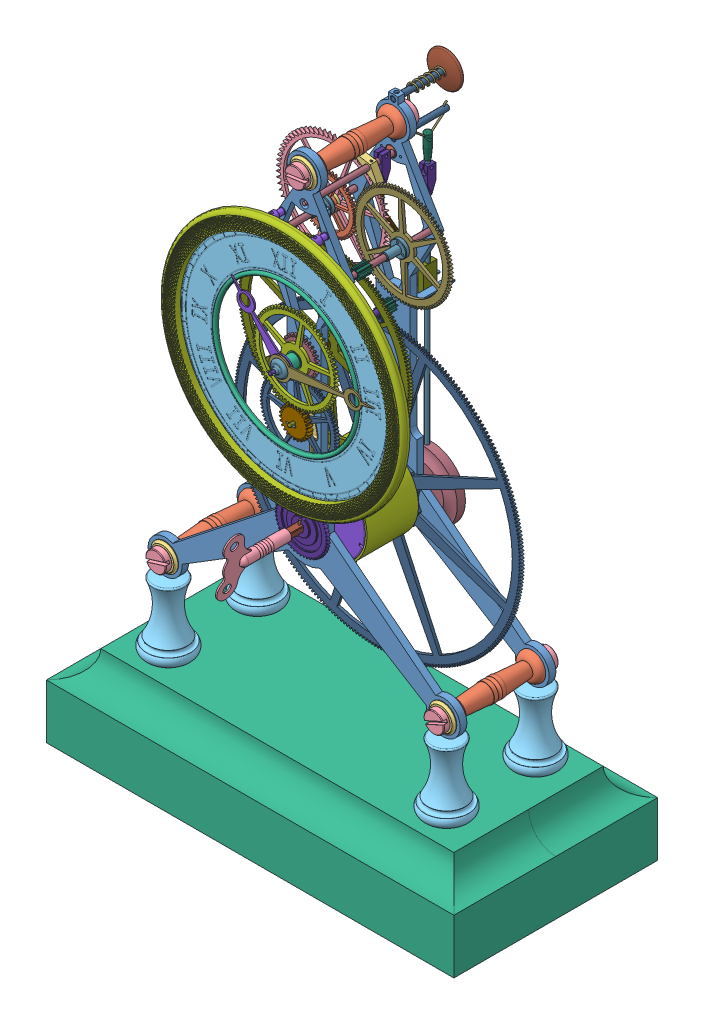
SolidWorks assembly clock, configuration Default. Lengths in mm.
Overall size (300 450.9 172.25).
96 component instances, 58 part files, 79 mates.
Components (placement in the parent):
- frame assy-1: frame assy [Default] at origin size (300 436.05 150)
  - Frame-1: Frame [Front] at origin size (229.79 321.19 5)
  - pillar-1: pillar [Default] at (0 115.9979 0) size (20 20 70.93)
  - pillar-2: pillar [Default] at (102.394 -180.1971 0) x (0.987351 0.158553 0) z (0 0 1) size (20 20 70.93)
  - pillar-3: pillar [Default] at (-102.394 -180.1971 0) x (0.959125 0.282984 0) z (0 0 1) size (20 20 70.93)
  - Frame-2: Frame [Back] at (0 0 -60.5) x (-1 0 0) z (0 0 -1) size (229.79 326.05 5)
  - washer-1: washer [Default] at (0 115.9979 7) x (0.258664 -0.965967 0) z (0 0 -1) size (20 20 2)
  - frame screw-1: frame screw [Default] at (0 115.9979 7) x (-0.137342 0.990524 0) z (0.990524 0.137342 0) size (15 20 15)
  - frame screw-2: frame screw [Default] at (-102.394 -180.1971 7) x (-0.292655 0.956218 0) z (0.956218 0.292655 0) size (15 20 15)
  - washer-2: washer [Default] at (-102.394 -180.1971 7) x (0.408549 -0.912737 0) z (0 0 -1) size (20 20 2)
  - frame screw-4: frame screw [Default] at (102.394 -180.1971 7) x (0.41203 -0.91117 0) z (-0.91117 -0.41203 0) size (15 20 15)
  - washer-4: washer [Default] at (102.394 -180.1971 7) x (-0.521444 0.853286 0) z (0 0 -1) size (20 20 2)
  - frame screw-6: frame screw [Default] at (102.394 -180.1971 -67.5) x (0.92649 0.37632 0) z (-0.37632 0.92649 0) size (15 20 15)
  - washer-6: washer [Default] at (102.394 -180.1971 -67.5) x (-0.965884 -0.258974 0) z (0 0 1) size (20 20 2)
  - frame screw-8: frame screw [Default] at (-102.394 -180.1971 -67.5) x (-0.887501 -0.460806 0) z (0.460806 -0.887501 0) size (15 20 15)
  - washer-8: washer [Default] at (-102.394 -180.1971 -67.5) x (-0.90624 -0.422764 0) z (0 0 1) size (20 20 2)
  - frame screw-10: frame screw [Default] at (0 115.9979 -67.5) x (0.741906 0.670504 0) z (-0.670504 0.741906 0) size (15 20 15)
  - washer-10: washer [Default] at (0 115.9979 -67.5) x (-0.81906 -0.573708 0) z (0 0 1) size (20 20 2)
  - foot-1: foot [Default] at (-102.394 -242.6971 2.5) x (0.145571 0 -0.989348) z (0.989348 0 0.145571) size (34 49.97 34)
  - foot-2: foot [Default] at (102.394 -242.6971 2.5) x (-0.043484 0 -0.999054) z (0.999054 0 -0.043484) size (34 49.97 34)
  - foot-3: foot [Default] at (102.394 -242.6971 -63) x (-0.257831 0 -0.96619) z (0.96619 0 -0.257831) size (34 49.97 34)
  - foot-4: foot [Default] at (-102.394 -242.6971 -63) x (-0.477152 0 -0.878821) z (0.878821 0 -0.477152) size (34 49.97 34)
  - base-1: base [Default] at (0 -302.6971 -30.25) size (300 60 150)
- barrel assy-1: barrel assy [Default] at (-35.1643 -5.8563 0) x (0.946025 0.324095 0) z (0 0 1) size (297.48 297.48 41.9)
  - barrel-1: barrel [Default] at (-66.9035 -193.9176 -9.3) x (-0.787259 0.616622 0) z (0 0 1) size (60 60 37.9)
  - barrel front cap-1: barrel front cap [Default] at (-66.9035 -193.9176 -9.3) x (-0.787259 0.616622 0) z (0 0 1) size (57.64 57.6 4.06)
  - barrel rear cap-1: barrel rear cap [Default] at (-66.9035 -193.9176 -51.2) x (0.787259 -0.616622 0) z (0 0 -1) size (57.6 57.6 4)
  - great wheel-1: great wheel [Default] at (85.4176 -175.4035 -49.2) x (-0.616622 -0.787259 0) z (0 0 1) size (211.89 211.9 2)
- barrel arbor-1: barrel arbor [Default] at (-106.8134 -89.4436 0) x (0.175635 0.984455 0) z (0 0 1) size (12 13 98.5)
- third wheel assy-1: third wheel assy [Default] at (-56.1519 28.3418 33.0931) x (0.998621 0.052495 0) z (0 0 1) size (71.86 71.91 71.9)
  - third wheel-1: third wheel [Default] at (57.6984 -32.7767 -72.5931) size (71.86 71.91 2)
  - top arbor-1: top arbor [Default] at (85.1984 27.2212 -93.5931) x (-0.979838 0.199793 0) z (0 0 -1) size (4 4 71.9)
  - escape collet-1: escape collet [Default] at (46.9887 81.0358 -78.5931) x (0.5 0.866025 0) z (0 0 -1) size (12 12 19)
  - great pinion-1: great pinion [Default] at (85.1984 27.2212 -37.9189) x (0.985823 -0.167791 0) z (0 0 1) size (8.11 8.11 10)
- center wheel assy-1: center wheel assy [Default] x (-0.992046 -0.125879 0) z (0 0 1) size (127.02 127.02 96.9)
  - great pinion-1: great pinion [Default] at (0 0 -50.2) size (8.11 8.11 10)
  - center wheel-1: center wheel [Default] at (0 0 -10) x (1 -0.000968 0) z (0 0 1) size (126.9 126.9 2)
  - center arbor-1: center arbor [Default] at origin size (4 4 96.9)
  - center collet-1: center collet [Default] at (0 0 -10) size (18 18 16)
  - motionwork taper pin-1: motionwork taper pin [Default] at (0 0 29.2) size (7 0.99 0.99)
- escape wheel assy-1: escape wheel assy [Default] at (-72.062 104.0263 94.3243) x (-0.943189 -0.03152 0.330758) z (0.331853 -0.138437 0.933118) size (103.61 105.97 68.71)
  - escape collet-1: escape collet [Default] at (-100.675 125.491 -95.1936) x (0.749598 0.639959 -0.168982) z (-0.330758 0.141033 -0.933118) size (12 12 19)
  - escape drive wheel-1: escape drive wheel [Default] at (-82.6947 -3.3757 -114.6141) x (0.871313 -0.334178 -0.359359) z (0.330758 -0.141033 0.933118) size (41.81 41.89 2)
  - escape spacer-1: escape spacer [Default] at (-83.3563 -3.0937 -116.4803) x (0.871313 -0.334178 -0.359359) z (0.330758 -0.141033 0.933118) size (12 12 2)
  - top arbor-1: top arbor [Default] at (-91.852 64.6878 -123.5861) x (-0.902259 0.242585 0.356484) z (-0.330758 0.141033 -0.933118) size (4 4 71.9)
  - escape wheel-1: escape wheel [Default] at (-84.0178 -2.8116 -118.3465) x (0.871313 -0.334178 -0.359359) z (0.330758 -0.141033 0.933118) size (83.42 83.5 2)
  - escape screw-1: escape screw [Default] at (-90.634 61.8662 -108.3692) x (0.929342 0.220591 -0.296079) z (-0.164081 0.965116 0.20403) size (4 12 4)
  - escape screw-2: escape screw [Default] at (-85.4406 66.2999 -109.5399) x (0.886772 0.384713 -0.256184) z (-0.322853 0.912198 0.252311) size (4 12 4)
  - escape screw-4: escape screw [Default] at (-84.5973 59.5509 -110.8589) x (0.837371 0.499848 -0.221271) z (-0.435211 0.854553 0.283426) size (4 12 4)
- motionwork hour assy-1: motionwork hour assy [Default] at (0 0 1.5) x (-0.682615 0.730778 0) z (0 0 1) size (85.92 61.91 12)
  - motionwork hour pipe-1: motionwork hour pipe [Default] at origin size (10.5 10.5 12)
  - hour wheel-1: hour wheel [Default] at (0 0 10.5) size (61.84 61.91 2)
  - motionwork hour hand-1: motionwork hour hand [Default] at origin size (63 16 1)
- motionwork reduction assy-1: motionwork reduction assy [Default] at (-19.1342 -75.1267 9) x (-0.878167 0.478354 0) z (0 0 1) size (56.89 56.89 5.5)
  - motionwork reduction pinion-1: motionwork reduction pinion [Default] at origin size (21.83 21.79 5.5)
  - motionwork reduction wheel-1: motionwork reduction wheel [Default] at origin size (56.89 56.89 2)
- motionwork minute assy-1: motionwork minute assy [Default] x (0.992046 0.125879 0) z (0 0 1) size (83.37 26.88 22)
  - motionwork minute pipe-1: motionwork minute pipe [Default] at origin size (7 7 18)
  - motionwork minute hand-1: motionwork minute hand [Default] at (0 0 3) size (78 16 1)
  - motionwork minute pinion-1: motionwork minute pinion [Default] at (0 0 8.5) size (26.73 26.88 2)
  - motionwork endcap-1: motionwork endcap [Default] at (0 0 23) size (12 12 4)
  - motionwork minute hand support-1: motionwork minute hand support [Default] at (0 0 22) size (12 12 3)
- motionwork reduction pivot-1: motionwork reduction pivot [Default] at (0 0 5) size (3 3 16.7)
- motionwork taper pin-1: motionwork taper pin [Default] at (0 -40 14.75) x (-1 0 0) z (0 0 1) size (7 0.99 0.99)
- barrel rachet wheel-1: barrel rachet wheel [Default] at (19.0564 -1.6866 7) x (0.984455 -0.175635 0) z (0 0 1) size (38.92 39 3)
- barrel click-1: barrel click [Default] at (0 0 7) size (17.17 29.82 2)
- barrel assy shoulder bolt-1: barrel assy shoulder bolt [Default] at (0 0 7) size (8.5 8.5 10.5)
- barrel click taper pin-1: barrel click taper pin [Default] at (0 -108.5 9) x (0.175635 0.984455 0) z (-0.867067 0.154692 0.473566) size (12 1.36 1.36)
- barrel click spring-1: barrel click spring [Default] at (0 0 5) size (8.83 43.99 1.56)
- winding key-1: winding key [Default] at (19.0564 -1.6866 18) x (0.984455 -0.175635 0) z (0 0 1) size (8 45 49)
- chapter ring assy-1: chapter ring assy [Default] at (0 0 17) size (180 180 23.64)
  - chapter ring-1: chapter ring [Default] at origin size (160 160 1)
  - chapter ring inner bezel-1: chapter ring inner bezel [Default] at (0 0 1) x (0.995864 0.090862 0) z (0 0 1) size (108 108 2.5)
  - chapter ring outer bezel-1: chapter ring outer bezel [Default] at origin size (180 180 5.64)
  - chapter ring post-1: chapter ring post [Default] at (15.9651 83.4872 -12) x (0 -1 0) z (0 0 1) size (6 6 17)
  - chapter ring post screw-1: chapter ring post screw [Default] at (-15.9651 83.4872 -5) size (6 6 7.04)
  - chapter ring post screw-2: chapter ring post screw [Default] at (15.9651 83.4872 -5) x (0.987351 0.158553 0) z (0 0 1) size (6 6 7.04)
  - chapter ring post-2: chapter ring post [Default] at (-15.9651 83.4872 -12) x (0 -1 0) z (0 0 1) size (6 6 17)
- suspension post-1: suspension post [Default] at (100.8262 102.1394 -65.5) x (0 1 0) z (0 0 1) size (4 4 40)
- suspension post-2: suspension post [Default] at (100.8262 77.1394 -65.5) x (0 1 0) z (0 0 1) size (4 4 40)
- suspension knob-1: suspension knob [Default] at (0 129.9979 -100) x (0.799165 0.601111 0) z (-0.601111 0.799165 0) size (26 3.95 26)
- suspension rope-1: suspension rope [Default] at (0 0 -74) size (8.06 39.53 26.52)
- pendulum assy-1: pendulum assy [Default] at (-0.6668 -128.0011 -86) x (-0.999996 0.00299 0) z (0 0 -1) size (50.8 250.4 12)
  - pendulum bob-1: pendulum bob [Default] at origin size (50.8 50.8 12)
  - pendulum rod-1: pendulum rod [Default] at (0 15 0) size (3 200 3)
  - pendulum hook-1: pendulum hook [Default] at (0 215 0) x (0 0 1) z (-1 0 0) size (5 18 5)
  - pendulum block-1: pendulum block [Default] at (0 116.5269 0) x (0 0 1) z (-1 0 0) size (10 25 4)
  - pendulum layout-1: pendulum layout [Default] at origin
  - crutch top-1: crutch top [Default] at origin size (7.17 20 7.17)
  - crutch rod-1: crutch rod [Default] at origin size (2 91.36 22) (hidden)
- top arbor-1: top arbor [Default] at (0 95.9979 -60.5) x (0.8635 0.504349 0) z (0 0 -1) size (4 4 71.9)
- crutch top-1: crutch top [Default] at (-0.598 -104.0012 -52.5) x (0.999996 -0.00299 0) z (0 0 1) size (7.17 20 7.17)
- crutch rod-1: crutch rod [Default] at (-0.2881 -0.3606 -72.5) x (0.999996 -0.00299 0) z (0 0 1) size (2 91.36 22)
- crutch pallet-1: crutch pallet [Default] at (-0.2911 -1.3606 -72.5) x (0 0 -1) z (0.999996 -0.00299 0) size (30 10 16)
- eccentric bushing-1: eccentric bushing [Default] at (0 191.9958 -65.5) x (-1 0 0) z (0 0 1) size (10.4 10.4 7)
- escape pallets-1: escape pallets [Default] at (0 0 -46.5) size (18.3 15.59 5)
Mates (geometry in assembly coordinates):
- GearMate2: gear = 8 : 180 mm: cylinder of center wheel assy-1/center wheel-1 through (0 0 -12) axis (0 0 1) radius 56.5496; cylinder of third wheel assy-1/top arbor-1 through (27.5 59.9979 5) axis (0 0 1) radius 2
- GearMate3: gear = 50 : 90 mm: cylinder of third wheel assy-1/third wheel-1 through (27.5 59.9979 -41.5) axis (0 0 1) radius 30.0469; cylinder of escape wheel assy-1/escape drive wheel-1 through (-27.5 59.9979 -41.5) axis (0 0 1) radius 16.0474
- Concentric32: concentric: cylinder of center wheel assy-1/center arbor-1 through (0 0 29.2339) axis (0 0 1) radius 1.25; cylinder of motionwork minute assy-1/motionwork minute pipe-1 through (0 0 23) axis (0 0 -1) radius 3.5
- Concentric33: concentric: cylinder of motionwork hour assy-1/motionwork hour pipe-1 through (0 0 21.5) axis (0 0 -1) radius 3.5; cylinder of motionwork minute assy-1/motionwork minute pipe-1 through (0 0 23) axis (0 0 -1) radius 3.5
- Distance2: distance = 0.5 mm: plane of motionwork hour assy-1/hour wheel-1 through (0 0 12) normal (0 0 1); plane of motionwork reduction assy-1/motionwork reduction pinion-1 through (-19.1342 -75.1267 12.5) normal (0 0 1)
- Coincident24: coincident: plane of center wheel assy-1/center arbor-1 through (0 0 0) normal (0.125879 -0.992046 0); plane of motionwork minute assy-1/motionwork minute pipe-1 through (0 0 0) normal (-0.125879 0.992046 0)
- GearMate4: gear = 30 : 80 mm: circle of motionwork reduction assy-1/motionwork reduction wheel-1; circle of motionwork minute assy-1/motionwork minute pinion-1
- GearMate5: gear = 70 : 25 mm: circle of motionwork reduction assy-1/motionwork reduction pinion-1; circle of motionwork hour assy-1/hour wheel-1
- Coincident26: coincident: plane of motionwork reduction pivot-1 through (0 0 5) normal (1 0 0); plane of motionwork taper pin-1 through (0 -40 14.75) normal (-1 0 0)
- Concentric35: concentric: cylinder of motionwork reduction pivot-1 through (-1.5 -40 14.75) axis (1 0 0) radius 0.4; circle of motionwork taper pin-1
- Concentric36: concentric: cylinder of barrel assy-1/barrel-1 through (0 -108.5 -49.2) axis (0 0 1) radius 30; cylinder of barrel arbor-1 through (0 -108.5 -65.5) axis (0 0 -1) radius 6
- Coincident27: coincident: plane of barrel assy-1/barrel rear cap-1 through (0 -108.5 -47.2) normal (0 0 1); plane of barrel arbor-1 through (5.9067 -109.5538 -47.2) normal (0 0 -1)
- GearMate6: gear = 8 : 290 mm: cylinder of barrel assy-1/great wheel-1 through (0 -108.5 -51.2) axis (0 0 1) radius 99.0488; cylinder of center wheel assy-1/center arbor-1 through (0 0 29.2339) axis (0 0 1) radius 2
- Concentric37: concentric: cylinder of frame assy-1/Frame-1 through (0 -108.5 0) axis (0 0 1) radius 3; cylinder of barrel arbor-1 through (0 -108.5 -65.5) axis (0 0 -1) radius 3
- Coincident28: coincident: plane of frame assy-1/Frame-1 through (0 0 0) normal (0 0 -1); plane of barrel arbor-1 through (2.9534 -109.0269 0) normal (0 0 1)
- Concentric38: concentric: cylinder of frame assy-1/Frame-1 through (-27.5 59.9979 5) axis (0 0 -1) radius 1.25; cylinder of escape wheel assy-1/top arbor-1 through (-27.5 59.9979 5) axis (0 0 1) radius 1.25
- Coincident29: coincident: plane of frame assy-1/Frame-1 through (0 0 0) normal (0 0 -1); plane of escape wheel assy-1/top arbor-1 through (-27.1737 61.2046 0) normal (0 0 1)
- Concentric39: concentric: cylinder of frame assy-1/Frame-1 through (0 0 0) axis (0 0 1) radius 1.25; cylinder of center wheel assy-1/center arbor-1 through (0 0 29.2339) axis (0 0 1) radius 1.25
- Coincident30: coincident: plane of frame assy-1/Frame-1 through (0 0 0) normal (0 0 -1); plane of center wheel assy-1/center arbor-1 through (-0.2518 1.9841 0) normal (0 0 1)
- Concentric40: concentric: cylinder of frame assy-1/Frame-1 through (27.5 59.9979 5) axis (0 0 -1) radius 1.25; cylinder of third wheel assy-1/top arbor-1 through (27.5 59.9979 5) axis (0 0 1) radius 1.25
- Coincident31: coincident: plane of frame assy-1/Frame-1 through (0 0 0) normal (0 0 -1); plane of third wheel assy-1/top arbor-1 through (27.3149 58.7617 0) normal (0 0 1)
- Concentric41: concentric: circle of frame assy-1/Frame-1; circle of motionwork reduction assy-1/motionwork reduction pinion-1
- Distance3: distance = 2 mm: plane of motionwork reduction assy-1/motionwork reduction wheel-1 through (-13.6351 -63.8817 7) normal (0 0 -1); plane of frame assy-1/Frame-1 through (0 0 5) normal (0 0 1)
- Coincident32: coincident: plane of frame assy-1/Frame-1 through (0 0 5) normal (0 0 1); plane of motionwork minute assy-1/motionwork minute pipe-1 through (0 0 5) normal (0 0 -1)
- Coincident33: coincident: plane of frame assy-1/Frame-1 through (0 0 5) normal (0 0 1); plane of motionwork reduction pivot-1 through (0 -40 5) normal (0 0 -1)
- Concentric42: concentric: cylinder of frame assy-1/Frame-1 through (0 -40 0) axis (0 0 1) radius 1.25; cylinder of motionwork reduction pivot-1 through (0 -40 0) axis (0 0 -1) radius 1.25
- Parallel4: parallel: plane of frame assy-1/Frame-1 through (-12.5 0 5) normal (-1 0 0); plane of motionwork reduction pivot-1 through (-1.5 -38.5 7) normal (-1 0 0)
- Coincident34: coincident: plane of frame assy-1/Frame-1 through (0 0 5) normal (0 0 1); plane of barrel rachet wheel-1 through (0 -108.5 5) normal (0 0 -1)
- Parallel5: parallel: plane of barrel arbor-1 through (-2.6929 -110.3775 5) normal (-0.984455 0.175635 0); plane of barrel rachet wheel-1 through (2.8089 -106.5416 5) normal (-0.984455 0.175635 0)
- Concentric43: concentric: circle of barrel arbor-1; circle of barrel rachet wheel-1
- Coincident35: coincident: plane of frame assy-1/Frame-1 through (0 0 5) normal (0 0 1); plane of barrel assy shoulder bolt-1 through (0 -80.5 5) normal (0 0 -1)
- Concentric44: concentric: cylinder of frame assy-1/Frame-1 through (0 -80.5 0) axis (0 0 1) radius 1; cylinder of barrel assy shoulder bolt-1 through (0 -80.5 5) axis (0 0 1) radius 2
- Concentric45: concentric: cylinder of barrel click-1 through (0 -80.5 5) axis (0 0 1) radius 2; cylinder of barrel assy shoulder bolt-1 through (0 -80.5 5) axis (0 0 1) radius 2
- Coincident36: coincident: plane of frame assy-1/Frame-1 through (0 0 5) normal (0 0 1); plane of barrel click-1 through (0 -80.5 5) normal (0 0 -1)
- Coincident37: coincident: plane of frame assy-1/Frame-1 through (0 0 0) normal (0 0 1); plane of assembly through (0 0 0) normal (0 0 1)
- Coincident38: coincident: plane of frame assy-1/Frame-1 through (0 0 0) normal (0 1 0); plane of assembly through (0 0 0) normal (0 1 0)
- Coincident39: coincident: plane of frame assy-1/Frame-1 through (0 0 0) normal (1 0 0); plane of assembly through (0 0 0) normal (1 0 0)
- Parallel6: parallel: plane of frame assy-1/Frame-1 through (17.5 -78.5 5) normal (1 0 0); plane of barrel click-1 through (5 -66.5 5) normal (1 0 0)
- Concentric46: concentric: circle of barrel arbor-1; circle of barrel click taper pin-1
- Coincident40: coincident: plane of barrel arbor-1 through (-106.8134 -89.4436 0) normal (0.175635 0.984455 0); plane of barrel click taper pin-1 through (0 -108.5 9) normal (0.175635 0.984455 0)
- Coincident41: coincident: plane of frame assy-1/Frame-1 through (0 0 5) normal (0 0 1); plane of barrel click spring-1 through (6 -47.5 5) normal (0 0 -1)
- Concentric47: concentric: cylinder of frame assy-1/Frame-1 through (6 -45 0) axis (0 0 1) radius 1; circle of barrel click spring-1
- Concentric48: concentric: cylinder of frame assy-1/Frame-1 through (6 -33 0) axis (0 0 1) radius 0.5; circle of barrel click spring-1
- Coincident42: coincident: plane of barrel arbor-1 through (0 -108.5 30) normal (0 0 1); plane of winding key-1 through (19.0564 -1.6866 30) normal (0 0 -1)
- Concentric49: concentric: cylinder of barrel arbor-1 through (0 -108.5 -65.5) axis (0 0 -1) radius 4; cylinder of winding key-1 through (0 -108.5 53) axis (0 0 -1) radius 4
- Parallel8: parallel: plane of barrel arbor-1 through (-2.6929 -110.3775 5) normal (-0.984455 0.175635 0); line of winding key-1 through (-2.1029 -105.4838 18) axis (-0.175635 -0.984455 0)
- Concentric53: concentric: circle of center wheel assy-1/center arbor-1; circle of chapter ring assy-1/chapter ring-1
- Coincident45: coincident: plane of frame assy-1/Frame-1 through (0 0 5) normal (0 0 1); plane of chapter ring assy-1/chapter ring post-1 through (18.2651 83.4872 5) normal (0 0 -1)
- Concentric54: concentric: cylinder of frame assy-1/Frame-1 through (15.9651 83.4872 5) axis (0 0 1) radius 0.8; cylinder of chapter ring assy-1/chapter ring post-1 through (15.9651 83.4872 5) axis (0 0 -1) radius 2
- Concentric55: concentric: cylinder of frame assy-1/Frame-2 through (0 129.9979 -60.5) axis (0 0 -1) radius 2; cylinder of suspension post-1 through (0 129.9979 -100.5) axis (0 0 1) radius 2
- Coincident46: coincident: plane of frame assy-1/Frame-2 through (0 0 -60.5) normal (0 0 1); plane of suspension post-1 through (0 129.9979 -60.5) normal (0 0 1)
- Parallel9: parallel: plane of frame assy-1/Frame-1 through (0 0 0) normal (0 1 0); plane of suspension post-1 through (100.8262 102.1394 -65.5) normal (0 1 0)
- Concentric56: concentric: cylinder of frame assy-1/Frame-2 through (0 104.9979 -60.5) axis (0 0 -1) radius 2; cylinder of suspension post-2 through (0 104.9979 -100.5) axis (0 0 1) radius 2
- Coincident48: coincident: plane of frame assy-1/Frame-2 through (0 0 -60.5) normal (0 0 1); plane of suspension post-2 through (0 104.9979 -60.5) normal (0 0 1)
- Parallel10: parallel: plane of frame assy-1/Frame-1 through (0 0 0) normal (0 1 0); plane of suspension post-2 through (100.8262 77.1394 -65.5) normal (0 1 0)
- Concentric57: concentric: cylinder of suspension post-1 through (0 129.9979 -100.5) axis (0 0 1) radius 2; cylinder of suspension knob-1 through (0 129.9979 -96) axis (0 0 -1) radius 2
- Coincident50: coincident: circle of suspension post-1; plane of suspension knob-1 through (0 129.9979 -100) normal (0 0 -1)
- Concentric60: concentric: cylinder of suspension post-2 through (0 102.9979 -98) axis (0 -1 0) radius 0.55; cylinder of suspension rope-1 through (0 106.9979 -98) axis (0 -1 0) radius 0.5
- Concentric61: concentric: cylinder of suspension post-2 through (0 102.9979 -74) axis (0 -1 0) radius 0.55; cylinder of suspension rope-1 through (0 102.6396 -74) axis (0 1 0) radius 0.5
- Concentric62: concentric: cylinder of suspension post-1 through (0 129.9979 -100.5) axis (0 0 1) radius 2; circle of suspension rope-1
- Parallel12: parallel: plane of frame assy-1/Frame-2 through (0 0 -65.5) normal (0 0 -1); plane of pendulum assy-1/pendulum bob-1 through (-0.6668 -128.0011 -92) normal (0 0 -1)
- Concentric65: concentric: cylinder of suspension rope-1 through (0 94.9979 -88) axis (0 0 1) radius 0.5; cylinder of pendulum assy-1/pendulum hook-1 through (0 94.9979 -83.5) axis (0 0 -1) radius 0.5
- Coincident55: coincident: plane of suspension rope-1 through (0 0 -86) normal (0 0 1); plane of pendulum assy-1/pendulum hook-1 through (-0.0239 86.998 -86) normal (0 0 -1)
- Concentric66: concentric: cylinder of frame assy-1/Frame-1 through (0 95.9979 0) axis (0 0 1) radius 1.25; cylinder of top arbor-1 through (0 95.9979 5) axis (0 0 1) radius 1.25
- Coincident56: coincident: plane of frame assy-1/Frame-1 through (0 0 0) normal (0 0 -1); plane of top arbor-1 through (-0.6304 97.0773 0) normal (0 0 1)
- Concentric67: concentric: circle of top arbor-1; circle of crutch top-1
- Concentric68: concentric: cylinder of crutch top-1 through (-0.015 90.9979 -52.5) axis (-0.00299 -0.999996 0) radius 1.5; cylinder of crutch rod-1 through (-0.015 90.9979 -52.5) axis (-0.00299 -0.999996 0) radius 1
- Coincident57: coincident: plane of crutch top-1 through (-0.015 90.9979 -52.5) normal (-0.00299 -0.999996 0); plane of crutch rod-1 through (-0.015 90.9979 -52.5) normal (0.00299 0.999996 0)
- Parallel13: parallel: plane of crutch top-1 through (-0.598 -104.0012 -52.5) normal (0.999996 -0.00299 0); plane of crutch rod-1 through (-0.2881 -0.3606 -72.5) normal (0.999996 -0.00299 0)
- Distance4: distance = 5 mm: plane of frame assy-1/Frame-2 through (0 0 -60.5) normal (0 0 1); plane of crutch top-1 through (-0.598 -104.0012 -55.5) normal (0 0 -1)
- Concentric69: concentric: cylinder of crutch rod-1 through (-0.2821 1.6394 -72.5) axis (-0.00299 -0.999996 0) radius 1; cylinder of crutch pallet-1 through (-0.2612 8.6393 -72.5) axis (-0.00299 -0.999996 0) radius 2
- Coincident58: coincident: plane of crutch rod-1 through (-0.2881 -0.3606 -72.5) normal (-0.00299 -0.999996 0); plane of crutch pallet-1 through (-0.2881 -0.3606 -72.5) normal (0.00299 0.999996 0)
- Parallel14: parallel: plane of crutch rod-1 through (-0.2881 -0.3606 -72.5) normal (0.999996 -0.00299 0); plane of crutch pallet-1 through (-0.2911 -1.3606 -72.5) normal (0.999996 -0.00299 0)
- Concentric70: concentric: cylinder of frame assy-1/Frame-2 through (-1.5 95.9979 -60.5) axis (0 0 -1) radius 4; cylinder of eccentric bushing-1 through (-1.5 95.9979 -60.5) axis (0 0 -1) radius 4
- Coincident59: coincident: plane of frame assy-1/Frame-2 through (0 0 -65.5) normal (0 0 -1); plane of eccentric bushing-1 through (-1.5 95.9979 -65.5) normal (0 0 1)
- Concentric71: concentric: cylinder of top arbor-1 through (0 95.9979 5) axis (0 0 1) radius 2; circle of eccentric bushing-1
- Parallel15: parallel: plane of pendulum assy-1/pendulum block-1 through (1.7564 13.5192 -81) normal (0.999996 -0.00299 0); plane of crutch pallet-1 through (7.7118 -0.3846 -98.5) normal (0.999996 -0.00299 0)
- Concentric72: concentric: cylinder of top arbor-1 through (0 95.9979 5) axis (0 0 1) radius 2; circle of escape pallets-1
- Distance5: distance = 3 mm: plane of escape pallets-1 through (-2.7854 98.7281 -46.5) normal (0 0 -1); plane of crutch top-1 through (-0.598 -104.0012 -49.5) normal (0 0 1)
